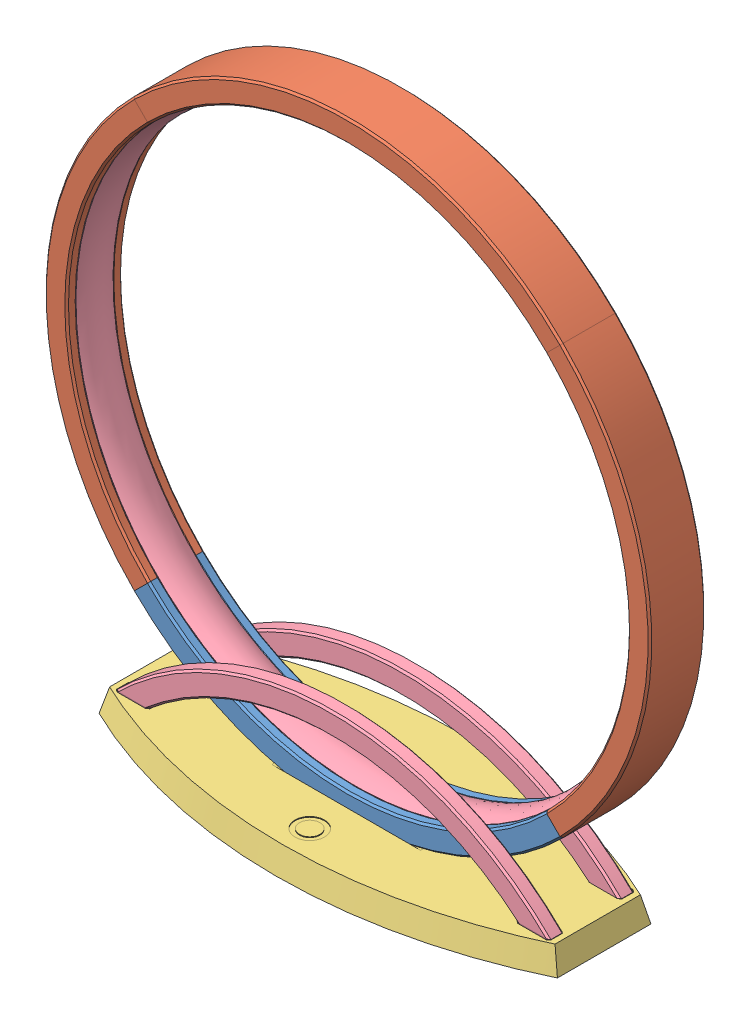
SolidWorks assembly lamp, configuration Défaut. Lengths in mm.
Overall size (461.47 461.47 106.97).
80 component instances, 24 part files, 30 mates.
Components (placement in the parent):
- arc-wire-1: arc-wire [Défaut] at (114.5919 110.7584 0) x (0.707107 0.707107 0) z (0 0 1) size (163.15 173.15 30)
- arc-2: arc [Défaut] at (-112.5395 58.6105 0) x (0.707107 -0.707107 0) z (0 0 1) size (163.15 173.15 30)
- arc-3: arc [Défaut] at (112.5395 283.6895 0) x (-0.707107 0.707107 0) z (0 0 1) size (163.15 173.15 30)
- arc-4: arc [Défaut] at (-112.5395 283.6895 0) x (-0.707107 -0.707107 0) z (0 0 1) size (163.15 173.15 30)
- support-1: support [Défaut] at origin size (246.97 13 106.97)
- support-arc-1: support-arc [Défaut] at (0 -103.7822 19) x (-1 0 0) z (0 0 -1) size (233.56 58.37 11.5)
- support-arc-2: support-arc [Défaut] at (0 -103.7822 -19) x (1 0 0) z (0 0 1) size (233.56 58.37 11.5)
- NanoV3 v4.step-1: NanoV3 v4.step [Défaut] at (-75.3 7.9 8.95) x (-1 0 0) z (0 0 -1) size (45.1 18 17.9)
  - PCB.step-1: PCB.step [Défaut] at origin size (45.1 18 17.9)
    - TopFace.step-1: TopFace.step [Défaut] at origin size (45.1 11.25 12.1)
      - Leds.step-1: Leds.step [Défaut] at origin size (4.2 0.5 12.1)
        - Led.step-1: Led.step [Défaut] at (3.25 0 -13.6) size (4.2 0.5 1.3)
        - Led.step-2: Led.step [Défaut] at (3.25 0 -17.2) size (4.2 0.5 1.3)
        - Led.step-3: Led.step [Défaut] at (3.25 0 -20.8) size (4.2 0.5 1.3)
        - Led (1).step-1: Led (1).step [Défaut] at (3.25 0 -10) size (4.2 0.5 1.3)
      - PinEnd.step-1: PinEnd.step [Défaut] at (0 0 -2.54) size (5.08 11.25 7.62) (hidden)
        - Pin.step-1: Pin.step [Défaut] at (25 1.6 57.68) x (1 0 0) z (0 0 -1) size (2.54 11.25 2.54)
        - Pin.step-2: Pin.step [Défaut] at (25 1.6 60.22) x (1 0 0) z (0 0 -1) size (2.54 11.25 2.54)
        - Pin.step-3: Pin.step [Défaut] at (25 1.6 62.76) x (1 0 0) z (0 0 -1) size (2.54 11.25 2.54)
        - Pin.step-4: Pin.step [Défaut] at (27.54 1.6 57.68) x (1 0 0) z (0 0 -1) size (2.54 11.25 2.54)
        - Pin.step-5: Pin.step [Défaut] at (27.54 1.6 60.22) x (1 0 0) z (0 0 -1) size (2.54 11.25 2.54)
        - Pin.step-6: Pin.step [Défaut] at (27.54 1.6 62.76) x (1 0 0) z (0 0 -1) size (2.54 11.25 2.54)
      - switch.step-1: switch.step [Défaut] at (1.3966 -1.5 22.3391) size (3 1.7 4.8)
      - chip1.step-1: chip1.step [Défaut] at origin size (11.76 1.3 11.76)
      - USB.step-1: USB.step [Défaut] at origin size (10.18 4.4 11.03)
      - Crystal.step-1: Crystal.step [Défaut] at origin size (2.71 1.1 2.71)
    - BottomFace.step-1: BottomFace.step [Défaut] at origin size (40.75 11.25 17.9)
      - PinRow2.step-1: PinRow2.step [Défaut] at (0 0 17.9) size (38.1 11.25 2.54) (hidden)
        - Pin (1).step-1: Pin (1).step [Défaut] at (45.58 0 32.1) size (2.54 11.25 2.54)
        - Pin (1).step-2: Pin (1).step [Défaut] at (48.12 0 32.1) size (2.54 11.25 2.54)
        - Pin (1).step-3: Pin (1).step [Défaut] at (50.66 0 32.1) size (2.54 11.25 2.54)
        - Pin (1).step-4: Pin (1).step [Défaut] at (53.2 0 32.1) size (2.54 11.25 2.54)
        - Pin (1).step-5: Pin (1).step [Défaut] at (55.74 0 32.1) size (2.54 11.25 2.54)
        - Pin (1).step-6: Pin (1).step [Défaut] at (58.28 0 32.1) size (2.54 11.25 2.54)
        - Pin (1).step-7: Pin (1).step [Défaut] at (60.82 0 32.1) size (2.54 11.25 2.54)
        - Pin (1).step-8: Pin (1).step [Défaut] at (63.36 0 32.1) size (2.54 11.25 2.54)
        - Pin (1).step-9: Pin (1).step [Défaut] at (43.04 0 32.1) size (2.54 11.25 2.54)
        - Pin (1).step-10: Pin (1).step [Défaut] at (40.5 0 32.1) size (2.54 11.25 2.54)
        - Pin (1).step-11: Pin (1).step [Défaut] at (37.96 0 32.1) size (2.54 11.25 2.54)
        - Pin (1).step-12: Pin (1).step [Défaut] at (35.42 0 32.1) size (2.54 11.25 2.54)
        - Pin (1).step-13: Pin (1).step [Défaut] at (32.88 0 32.1) size (2.54 11.25 2.54)
        - Pin (1).step-14: Pin (1).step [Défaut] at (30.34 0 32.1) size (2.54 11.25 2.54)
        - Pin (1).step-15: Pin (1).step [Défaut] at (27.8 0 32.1) size (2.54 11.25 2.54)
      - PinRow1.step-1: PinRow1.step [Défaut] at origin size (38.1 11.25 2.54) (hidden)
        - Pin.step-1: Pin.step [Défaut] at (45.58 0 -32.1) size (2.54 11.25 2.54)
        - Pin.step-2: Pin.step [Défaut] at (48.12 0 -32.1) size (2.54 11.25 2.54)
        - Pin.step-3: Pin.step [Défaut] at (50.66 0 -32.1) size (2.54 11.25 2.54)
        - Pin.step-4: Pin.step [Défaut] at (53.2 0 -32.1) size (2.54 11.25 2.54)
        - Pin.step-5: Pin.step [Défaut] at (55.74 0 -32.1) size (2.54 11.25 2.54)
        - Pin.step-6: Pin.step [Défaut] at (58.28 0 -32.1) size (2.54 11.25 2.54)
        - Pin.step-7: Pin.step [Défaut] at (60.82 0 -32.1) size (2.54 11.25 2.54)
        - Pin.step-8: Pin.step [Défaut] at (63.36 0 -32.1) size (2.54 11.25 2.54)
        - Pin.step-9: Pin.step [Défaut] at (43.04 0 -32.1) size (2.54 11.25 2.54)
        - Pin.step-10: Pin.step [Défaut] at (40.5 0 -32.1) size (2.54 11.25 2.54)
        - Pin.step-11: Pin.step [Défaut] at (37.96 0 -32.1) size (2.54 11.25 2.54)
        - Pin.step-12: Pin.step [Défaut] at (35.42 0 -32.1) size (2.54 11.25 2.54)
        - Pin.step-13: Pin.step [Défaut] at (32.88 0 -32.1) size (2.54 11.25 2.54)
        - Pin.step-14: Pin.step [Défaut] at (30.34 0 -32.1) size (2.54 11.25 2.54)
        - Pin.step-15: Pin.step [Défaut] at (27.8 0 -32.1) size (2.54 11.25 2.54)
      - Resistors.step-1: Resistors.step [Défaut] at origin size (32.5 1 11.3)
        - Res.step-1: Res.step [Défaut] at (12.2 1.6 29.15) x (0 0 -1) z (1 0 0) size (1.3 1 4)
        - Res.step-2: Res.step [Défaut] at (12.2 1.6 24.6) x (0 0 -1) z (1 0 0) size (1.3 1 4)
        - Res.step-3: Res.step [Défaut] at (-2.9 1.6 23.1) x (0 0 -1) z (1 0 0) size (1.3 1 4)
        - Res.step-4: Res.step [Défaut] at (-2.9 1.6 26.2) x (0 0 -1) z (1 0 0) size (1.3 1 4)
        - Res.step-5: Res.step [Défaut] at (-16.3 1.6 19.15) x (0 0 -1) z (1 0 0) size (1.3 1 4)
      - caps.step-1: caps.step [Défaut] at origin size (33.2 1.51 4.35)
        - cap.step-1: cap.step [Défaut] at (68.25 1.6 43.825) x (-1 0 0) z (0 0 -1) size (3.7 1.51 1.65)
        - cap.step-2: cap.step [Défaut] at (-14.35 1.6 -32.125) size (3.7 1.51 1.65)
      - respacks.step-1: respacks.step [Défaut] at origin size (3.22 1.08 8.5)
        - respack.step-1: respack.step [Défaut] at (-0.85 1.6 -21.8) size (3.22 1.08 3.5)
        - respack.step-2: respack.step [Défaut] at (-0.85 1.6 -26.8) size (3.22 1.08 3.5)
      - Chip.step-1: Chip.step [Défaut] at origin size (10 1.5 8.03)
      - diode.step-1: diode.step [Défaut] at (0.15 1.6 -28.35) size (1.6 1 4.3)
      - vreg.step-1: vreg.step [Défaut] at (-16.3 1.6 -15.5) size (8.5 1.6 6)
    - PCB-0.step-1: PCB-0.step [Défaut] at origin size (43.7 1.6 17.9)
- Micro-USB_breakout.step-1: Micro-USB_breakout.step [Défaut] at (6.65 6.4 -49.0074) x (0 0 1) z (0 -1 0) size (16.21 13.3 4.6)
- 3-Pin JST Female.step-1: 3-Pin JST Female.step [Défaut] at (82.7151 11 3.5653) x (0.99213 0 0.125209) z (0.125209 0 -0.99213) size (18.25 9.65 11.5)
- jst_sm2_54_3-pin_male.step-1: jst_sm2_54_3-pin_male.step [Défaut] at (95.4072 6.463 12.2123) x (0.125209 0 -0.99213) z (-0.99213 0 -0.125209) size (13.98 7.44 11.95)
- touch button TTP223-2: touch button TTP223 [По умолчанию] at (0 11 33.6628) x (1 0 0) z (0 1 0) size (10.5 14.5 2)
- difuser-1: difuser [Défaut] at (0 171.15 0) x (0.999776 -0.021173 0) z (0 0 1) size (312.3 312.3 20)
Mates (geometry in assembly coordinates):
- Coaxiale1: concentric aligned: cylinder of arc-wire-1 through (0 171.15 0) axis (0 0 -1) radius 159.1549; cylinder of arc-2 through (0 171.15 0) axis (0 0 -1) radius 159.1549
- Coïncidente1: coincident aligned: plane of arc-wire-1 through (106.8827 64.2673 15) normal (0 0 1); plane of arc-2 through (-106.8827 64.2673 15) normal (0 0 1)
- Coïncidente2: coincident anti-aligned: plane of arc-wire-1 through (-112.5395 58.6105 0) normal (-0.707107 0.707107 0); plane of arc-2 through (-112.5395 58.6105 0) normal (0.707107 -0.707107 0)
- Coaxiale2: concentric aligned: cylinder of arc-3 through (0 171.15 0) axis (0 0 -1) radius 159.1549; cylinder of arc-4 through (0 171.15 0) axis (0 0 -1) radius 159.1549
- Coïncidente3: coincident anti-aligned: plane of arc-3 through (112.5395 283.6895 0) normal (-0.707107 0.707107 0); plane of arc-4 through (112.5395 283.6895 0) normal (0.707107 -0.707107 0)
- Coïncidente4: coincident aligned: plane of arc-3 through (106.8827 278.0327 15) normal (0 0 1); plane of arc-4 through (-106.8827 278.0327 15) normal (0 0 1)
- Coaxiale3: concentric aligned: cylinder of arc-wire-1 through (0 171.15 0) axis (0 0 -1) radius 159.1549; cylinder of arc-4 through (0 171.15 0) axis (0 0 -1) radius 159.1549
- Coïncidente5: coincident aligned: plane of arc-wire-1 through (106.8827 64.2673 15) normal (0 0 1); plane of arc-3 through (106.8827 278.0327 15) normal (0 0 1)
- Coïncidente6: coincident anti-aligned: plane of arc-wire-1 through (112.5395 58.6105 0) normal (0.707107 0.707107 0); plane of arc-3 through (112.5395 58.6105 0) normal (-0.707107 -0.707107 0)
- Coaxiale4: concentric aligned: cylinder of arc-wire-1 through (0 171.15 0) axis (0 0 -1) radius 163.1549; cylinder of support-1 through (0 171.15 15.5) axis (0 0 -1) radius 163.15
- Largeur1: width anti-aligned: plane of support-1 through (0 171.15 -15.5) normal (0 0 1); plane of arc-wire-1 through (0 171.15 15.5) normal (0 0 -1); plane of support-1 through (115.368 55.782 -15) normal (0 0 -1); plane of arc-wire-1 through (106.8827 64.2673 15) normal (0 0 1)
- Coïncidente17: coincident anti-aligned: plane of arc-wire-1 through (106.8827 64.2673 15) normal (0 0 1); plane of support-arc-1 through (116.7822 13 15) normal (0 0 -1)
- Coïncidente18: coincident: point of support-arc-1
- Coïncidente20: coincident anti-aligned: plane of support-1 through (0 11 0) normal (0 -1 0); plane of NanoV3 v4.step-1/PCB.step-1/BottomFace.step-1/Chip.step-1 through (-97.15 11 0) normal (0 1 0)
- Largeur2: width aligned: plane of NanoV3 v4.step-1/PCB.step-1/PCB-0.step-1 through (-75.3 7.9 -8.95) normal (0 0 -1); plane of support-1 through (-119 7.9 8.95) normal (0 0 1); plane of NanoV3 v4.step-1/PCB.step-1/PCB-0.step-1 through (-119 11 9.89) normal (0 0 -1); plane of support-1 through (-119 11 -9.89) normal (0 0 1)
- Coïncidente21: coincident anti-aligned: plane of support-1 through (-119 11 9.89) normal (1 0 0); plane of NanoV3 v4.step-1/PCB.step-1/PCB-0.step-1 through (-119 7.9 -8.95) normal (-1 0 0)
- Coïncidente22: coincident anti-aligned: plane of support-1 through (0 8 0) normal (0 -1 0); plane of Micro-USB_breakout.step-1 through (0.0039 8 -41.3006) normal (0 1 0)
- Coïncidente24: coincident anti-aligned: plane of support-1 through (-7.5 8 -49) normal (0 0 1); plane of Micro-USB_breakout.step-1 through (-6.65 6.4 -49) normal (0 0 -1)
- Largeur3: width anti-aligned: plane of Micro-USB_breakout.step-1 through (-6.65 6.4 -33.4) normal (-1 0 0); plane of support-1 through (6.65 6.4 -49.0074) normal (1 0 0); plane of Micro-USB_breakout.step-1 through (-7.5 8 -32) normal (1 0 0); plane of support-1 through (7.5 8 -32) normal (-1 0 0)
- Coïncidente28: coincident anti-aligned: plane of 3-Pin JST Female.step-1 through (84.8234 11 3.8314) normal (0.99213 0 0.125209); plane of jst_sm2_54_3-pin_male.step-1 through (83.9482 6.463 10.7662) normal (-0.99213 0 -0.125209)
- Largeur5: width anti-aligned: plane of jst_sm2_54_3-pin_male.step-1 through (96.7807 6.463 1.3288) normal (0.125209 0 -0.99213); plane of jst_sm2_54_3-pin_male.step-1 through (95.784 6.463 9.2262) normal (-0.125209 0 0.99213); plane of 3-Pin JST Female.step-1 through (85.4181 4 -0.8813) normal (-0.125209 0 0.99213); plane of 3-Pin JST Female.step-1 through (84.2286 4 8.544) normal (0.125209 0 -0.99213)
- Largeur6: width aligned: plane of jst_sm2_54_3-pin_male.step-1 through (95.4072 4.5 12.2123) normal (0 -1 0); plane of jst_sm2_54_3-pin_male.step-1 through (95.4072 9.5 12.2123) normal (0 1 0); plane of 3-Pin JST Female.step-1 through (85.4181 10 -0.8813) normal (0 -1 0); plane of 3-Pin JST Female.step-1 through (85.4181 4 -0.8813) normal (0 1 0)
- Coïncidente29: coincident anti-aligned: plane of support-1 through (82.5759 11 8.7874) normal (0 -1 0); plane of 3-Pin JST Female.step-1 through (82.7151 11 3.5653) normal (0 1 0)
- Coïncidente30: coincident anti-aligned: plane of support-1 through (0 12 0) normal (0 -1 0); plane of touch button TTP223-2 through (0 12 33.6628) normal (0 1 0)
- Largeur7: width aligned: plane of touch button TTP223-2 through (-5.25 12 40.9128) normal (-1 0 0); plane of touch button TTP223-2 through (5.25 12 40.9128) normal (1 0 0); plane of support-1 through (-6 12 41.1628) normal (0.984808 -0.173648 0); plane of support-1 through (6 12 41.1628) normal (-0.984808 -0.173648 0)
- Largeur8: width aligned: plane of support-1 through (-6 12 26.1628) normal (0 -0.173648 0.984808); plane of support-1 through (-6 12 41.1628) normal (0 -0.173648 -0.984808); plane of touch button TTP223-2 through (5.25 12 26.4128) normal (0 0 -1); plane of touch button TTP223-2 through (5.25 12 40.9128) normal (0 0 1)
- Parallèle2: parallel anti-aligned: cylinder of arc-wire-1 through (0 178.2225 -4) axis (0 -1 0) radius 4; cylinder of support-1 through (0 0 -4) axis (0 1 0) radius 4
- Coaxiale7: concentric anti-aligned: cylinder of arc-wire-1 through (0 171.15 0) axis (0 0 -1) radius 159.1549; cylinder of difuser-1 through (0 171.15 0) axis (0 0 1) radius 156.15
- Largeur9: width anti-aligned: plane of difuser-1 through (-3.3062 15.035 10) normal (0 0 1); plane of difuser-1 through (-3.3062 15.035 -10) normal (0 0 -1); plane of arc-wire-1 through (106.8827 64.2673 10) normal (0 0 -1); plane of arc-wire-1 through (106.8827 64.2673 -10) normal (0 0 1)
- Coïncidente31: coincident: plane of support-1 through (0 13 -230.1667) normal (0 1 0); line of support-arc-1 through (-115.3636 13 23) axis (1 0 0)
